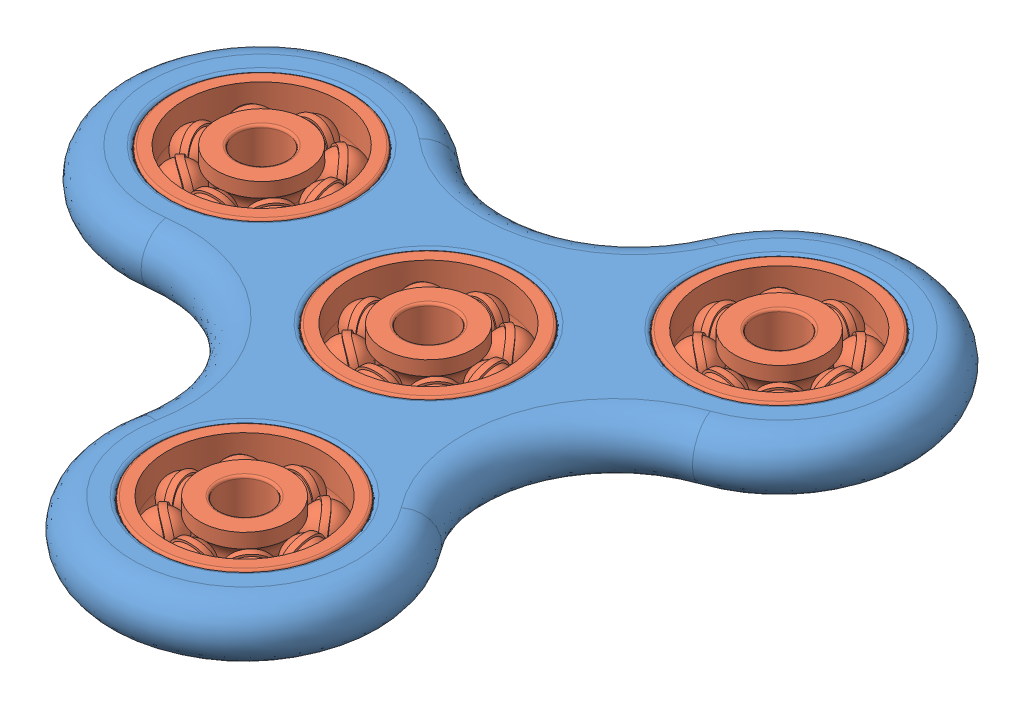
SolidWorks assembly Fidget, configuration Default. Lengths in mm.
Overall size (100.28 7 104.96).
5 component instances, 2 part files, 11 mates.
Components (placement in the parent):
- Part1_Body-1: Part1_Body [Default] x (0.285867 0 -0.958269) z (0.958269 0 0.285867) size (85.96 7 79)
- angular contact ball bearing_68_bsi-1: angular contact ball bearing_68_bsi [BS 6267 ABB - 36 - Full,DE,AC,Full_68] at (0 3.5 0) x (0 -1 0) z (0.996752 0 -0.080532) size (7 22 22)
- angular contact ball bearing_68_bsi-2: angular contact ball bearing_68_bsi [BS 6267 ABB - 36 - Full,DE,AC,Full_68] at (6.947 3.5 29.1846) x (0 -1 0) z (-0.660996 0 0.75039) size (7 22 22)
- angular contact ball bearing_68_bsi-4: angular contact ball bearing_68_bsi [BS 6267 ABB - 36 - Full,DE,AC,Full_68] at (-28.7481 3.5 -8.576) x (0 -1 0) z (0.126662 0 0.991946) size (7 22 22)
- angular contact ball bearing_68_bsi-5: angular contact ball bearing_68_bsi [BS 6267 ABB - 36 - Full,DE,AC,Full_68] at (21.8011 3.5 -20.6086) x (0 -1 0) z (0.711744 0 0.702439) size (7 22 22)
Mates (geometry in assembly coordinates):
- Concentric1: concentric aligned: cylinder of Part1_Body-1 through (-0.0002 6.9981 -0.0006) axis (0.000048 -1 0.000174) radius 11; cylinder of angular contact ball bearing_68_bsi-1 through (0.0001 24.1375 0) axis (-0.000003 -1 0) radius 3
- Concentric2: concentric aligned: cylinder of Part1_Body-1 through (-28.7451 6.9952 -8.5872) axis (0.000048 -1 0.000174) radius 11; cylinder of angular contact ball bearing_68_bsi-2 through (-28.756 24.1243 -8.5787) axis (-0.000041 -1 -0.000013) radius 3
- Concentric3: concentric aligned: cylinder of Part1_Body-1 through (21.8085 6.9956 -20.6011) axis (0.000048 -1 0.000174) radius 11; cylinder of angular contact ball bearing_68_bsi-4 through (21.799 24.1385 -20.619) axis (-0.00011 -1 -0.00001) radius 3
- Concentric4: concentric aligned: cylinder of Part1_Body-1 through (6.9361 7.0035 29.1865) axis (0.000048 -1 0.000174) radius 11; cylinder of angular contact ball bearing_68_bsi-5 through (6.9594 24.1607 29.2024) axis (0.00001 -1 -0.000005) radius 3
- Coincident1: coincident aligned: plane of Part1_Body-1 through (-0.0002 6.9981 -0.0006) normal (-0.000048 1 -0.000174); plane of angular contact ball bearing_68_bsi-5 through (13.5142 7.0233 22.4996) normal (-0.00001 1 0.000005)
- Concentric5: concentric aligned: cylinder of Part1_Body-1 through (-0.0002 6.9981 -0.0006) axis (0.000048 -1 0.000174) radius 11; cylinder of angular contact ball bearing_68_bsi-1 through (0.0001 24.1375 0) axis (-0.000003 -1 0) radius 11
- Coincident2: coincident aligned: plane of Part1_Body-1 through (-0.0002 6.9981 -0.0006) normal (-0.000048 1 -0.000174); plane of angular contact ball bearing_68_bsi-1 through (-0.6353 7 -9.3535) normal (0.000003 1 0)
- Coincident3: coincident aligned: plane of Part1_Body-1 through (-0.0002 6.9981 -0.0006) normal (-0.000048 1 -0.000174); plane of angular contact ball bearing_68_bsi-4 through (31.0863 7 -21.8851) normal (0.00011 1 0.00001)
- Coincident4: coincident aligned: plane of Part1_Body-1 through (-0.0002 6.9981 -0.0006) normal (-0.000048 1 -0.000174); plane of angular contact ball bearing_68_bsi-2 through (-21.7486 6.9864 -2.3517) normal (0.000041 1 0.000013)
- Concentric6: concentric anti-aligned: cylinder of angular contact ball bearing_68_bsi-1 through (0.0001 24.1375 0) axis (-0.000003 -1 0) radius 3
- Coincident5: coincident anti-aligned: plane of Part1_Body-1 through (0.0002 -0.0019 0.0006) normal (0.000048 -1 0.000174)
